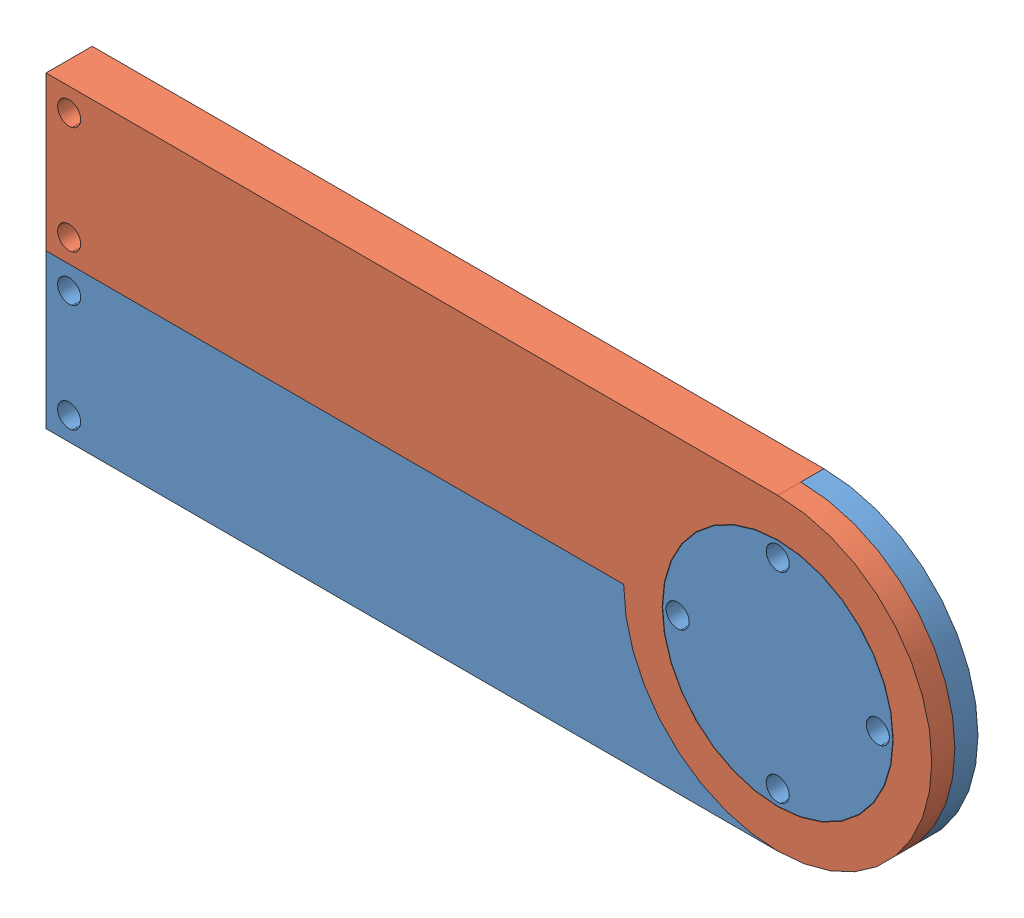
SolidWorks assembly barre basse, configuration Défaut. Lengths in mm.
Overall size (115 40 6).
2 component instances, 2 part files, 3 mates.
Components (placement in the parent):
- alpha bis-1: alpha bis [Défaut] at (-56.8653 -38.185 96.0458) size (115 40 6)
- beta-2: beta [Défaut] at (-67.0844 -13.8721 102.0458) x (-1 0 0) z (0 0 -1) size (115 40 6)
Mates (geometry in assembly coordinates):
- Coïncidente1: coincident anti-aligned: plane of alpha bis-1 through (-23.873 -10.0857 99.0458) normal (0 0 1); plane of beta-2 through (-23.873 -10.0857 99.0458) normal (0 0 -1)
- Coaxiale1: concentric aligned: cylinder of alpha bis-1 through (-23.873 -10.0857 99.0458) axis (0 0 1) radius 14.95; cylinder of beta-2 through (-23.873 -10.0857 96.0458) axis (0 0 1) radius 15
- Angle1: planar angle = 0 rad anti-aligned: plane of alpha bis-1 through (-56.8653 -30.0857 102.0458) normal (0 -1 0); plane of beta-2 through (-67.0844 9.9143 96.0458) normal (0 1 0)
